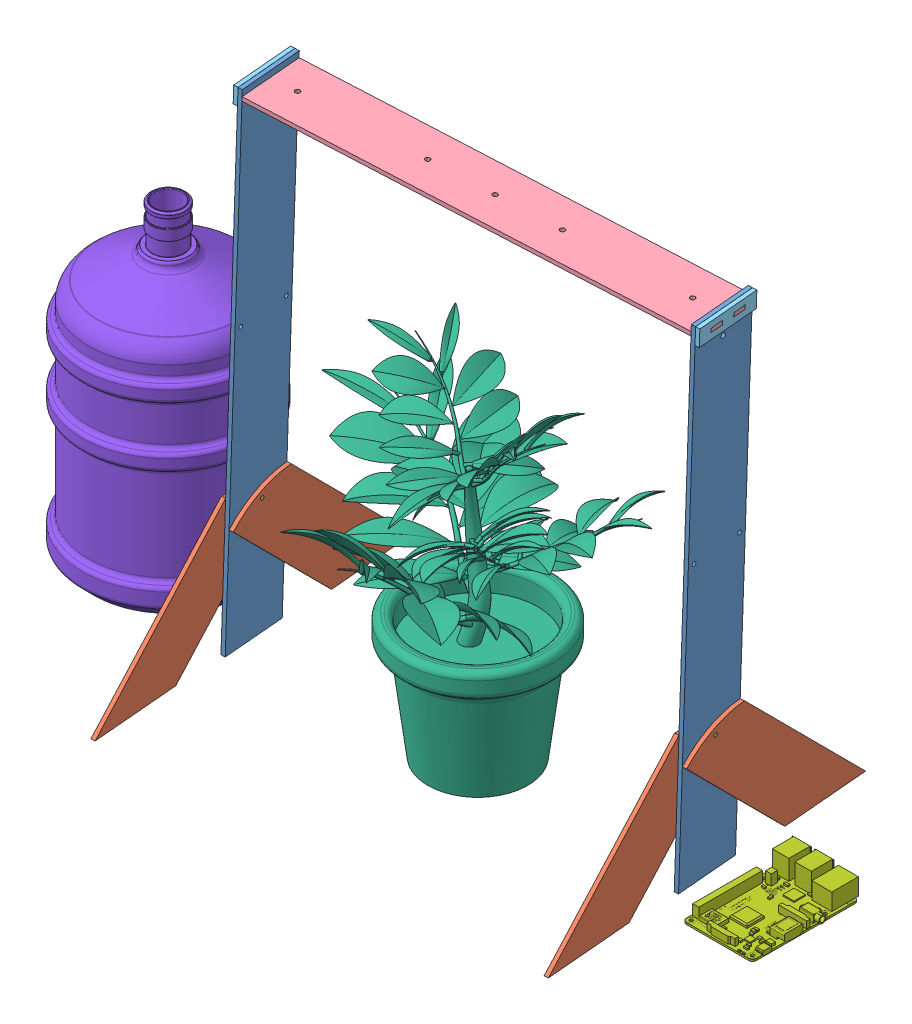
SolidWorks assembly Plant_Frame_Assem, configuration Default. Lengths in mm.
Overall size (564.8 413.02 298.87).
16 component instances, 8 part files, 13 mates.
Components (placement in the parent):
- Assem5^Plant_Frame_Assem-1: Assem5^Plant_Frame_Assem [Default] at (-8.3059 -105.6265 90.45) x (0 -1 0) z (0 0 1) size (400.06 26.56 270.71) (virtual)
  - Left_Right-1: Left_Right [Default] at (-16.0185 -211.6798 -1.7798) x (0.99946 -0.032815 0.001377) z (0.001377 0.083777 0.996484) size (400 3.17 50)
  - Left_Right_Support-1: Left_Right_Support [Default] at (308.6675 -227.6012 -25.9782) x (-0.001377 -0.083777 -0.996484) z (0.99946 -0.032815 0.001377) size (160.36 3.17 110.36)
  - Circular-1: Circular [Default] at (283.6796 -226.8251 -26.0089) x (0.99946 -0.032815 0.001377) z (0.001377 0.083777 0.996484) size (3 9.53 3)
  - Left_Right_Support-2: Left_Right_Support [Default] at (308.9801 -218.1148 -26.7762) x (0.001377 0.083777 0.996484) z (0.99946 -0.032815 0.001377) size (160.36 3.17 110.36)
- Assem5^Plant_Frame_Assem-2: Assem5^Plant_Frame_Assem [Default] at (326.5056 -116.6581 62.2862) x (0 -1 0) z (0 0 1) size (400.06 26.56 270.71) (virtual)
  - Left_Right-1: Left_Right [Default] at (-16.0185 -211.6798 -1.7798) x (0.99946 -0.032815 0.001377) z (0.001377 0.083777 0.996484) size (400 3.17 50)
  - Left_Right_Support-1: Left_Right_Support [Default] at (308.6675 -227.6012 -25.9782) x (-0.001377 -0.083777 -0.996484) z (0.99946 -0.032815 0.001377) size (160.36 3.17 110.36)
  - Circular-1: Circular [Default] at (283.6796 -226.8251 -26.0089) x (0.99946 -0.032815 0.001377) z (0.001377 0.083777 0.996484) size (3 9.53 3)
  - Left_Right_Support-2: Left_Right_Support [Default] at (308.9801 -218.1148 -26.7762) x (0.001377 0.083777 0.996484) z (0.99946 -0.032815 0.001377) size (160.36 3.17 110.36)
- Top-1: Top [Default] at (-53.3616 -103.3121 49.5545) x (-0.995944 0.032815 0.083777) z (-0.083777 0.001377 -0.996484) size (345.7 3.17 50)
- Left_Right_Clamp_3-1: Left_Right_Clamp_3 [Default] at (-223.5773 -102.5843 88.9543) x (-0.083777 0.001377 -0.996484) z (-0.032815 -0.99946 0.001377) size (50 3.17 13.17)
- Left_Right_Clamp_3-2: Left_Right_Clamp_3 [Default] at (117.5527 -113.9991 60.2588) x (-0.083777 0.001377 -0.996484) z (-0.032815 -0.99946 0.001377) size (50 3.17 13.17)
- POT-1: POT [Default] at (-62.6435 -490.8322 -76.7358) size (233.41 266.72 222.71)
- Rpi3Bplus-1: Rpi3Bplus [Default] at (180.3437 -502.3468 76.9406) x (0 0 -1) z (1 0 0) size (87.03 17.52 58.47)
- 20 ltr water bottle-1: 20 ltr water bottle [Default] at (-312.9838 -576.0338 51.5192) size (138 246 138)
Mates (geometry in assembly coordinates):
- Coincident5: coincident anti-aligned: plane of Assem5^Plant_Frame_Assem-1/Left_Right-1 through (-220.3388 -94.6544 48.5518) normal (-0.032815 -0.99946 0.001377); plane of Top-1 through (-53.2574 -100.1388 49.5502) normal (0.032815 0.99946 -0.001377)
- Coincident6: coincident anti-aligned: plane of Assem5^Plant_Frame_Assem-2/Left_Right-1 through (114.4727 -105.686 20.388) normal (-0.032815 -0.99946 0.001377); plane of Top-1 through (-53.2574 -100.1388 49.5502) normal (0.032815 0.99946 -0.001377)
- Coincident7: coincident anti-aligned: plane of Assem5^Plant_Frame_Assem-1/Left_Right-1 through (-219.9857 -89.608 88.6703) normal (-0.995944 0.032815 0.083777); plane of Left_Right_Clamp_3-1 through (-220.4152 -102.6885 88.6883) normal (0.995944 -0.032815 -0.083777)
- Coincident8: coincident anti-aligned: plane of Top-1 through (-53.2574 -100.1388 49.5502) normal (0.032815 0.99946 -0.001377); plane of Left_Right_Clamp_3-1 through (-222.6631 -94.564 58.7826) normal (-0.032815 -0.99946 0.001377)
- Coincident9: coincident anti-aligned: plane of Assem5^Plant_Frame_Assem-1/Left_Right-1 through (-216.8236 -89.7122 88.4043) normal (0.995944 -0.032815 -0.083777); plane of Top-1 through (-219.0821 -94.6751 63.4991) normal (-0.995944 0.032815 0.083777)
- Coincident10: coincident anti-aligned: plane of Assem5^Plant_Frame_Assem-1/Left_Right-1 through (-220.4429 -97.8277 48.5562) normal (0.083777 -0.001377 0.996484); plane of Top-1 through (-54.5141 -100.1181 34.6029) normal (-0.083777 0.001377 -0.996484)
- Coincident11: coincident anti-aligned: plane of Top-1 through (-54.5141 -100.1181 34.6029) normal (-0.083777 0.001377 -0.996484); plane of Left_Right_Clamp_3-1 through (-223.5993 -97.5486 48.8219) normal (0.083777 -0.001377 0.996484)
- Coincident12: coincident anti-aligned: plane of Assem5^Plant_Frame_Assem-2/Left_Right-1 through (117.9879 -100.7438 60.2405) normal (0.995944 -0.032815 -0.083777); plane of Left_Right_Clamp_3-2 through (117.5527 -113.9991 60.2588) normal (-0.995944 0.032815 0.083777)
- Coincident13: coincident: plane of Assem5^Plant_Frame_Assem-2/Left_Right-1 through (114.8258 -100.6396 60.5065) normal (-0.995944 0.032815 0.083777); line of Top-1 through (110.4728 -105.568 10.6892) axis (0.083777 -0.001377 0.996484)
- Coincident14: coincident anti-aligned: plane of Assem5^Plant_Frame_Assem-2/Left_Right-1 through (115.2063 -108.8731 30.3572) normal (0.032815 0.99946 -0.001377); plane of Top-1 through (-53.3616 -103.3121 49.5545) normal (-0.032815 -0.99946 0.001377)
- Coincident15: coincident anti-aligned: plane of Assem5^Plant_Frame_Assem-2/Left_Right-1 through (114.3686 -108.8593 20.3924) normal (0.083777 -0.001377 0.996484); plane of Top-1 through (117.6349 -105.7902 20.122) normal (-0.083777 0.001377 -0.996484)
- Coincident16: coincident anti-aligned: plane of Top-1 through (-53.3616 -103.3121 49.5545) normal (-0.032815 -0.99946 0.001377); plane of Left_Right_Clamp_3-2 through (118.3684 -108.9772 30.0912) normal (0.032815 0.99946 -0.001377)
- Coincident17: coincident anti-aligned: plane of Left_Right_Clamp_3-2 through (117.5307 -108.9635 20.1264) normal (0.083777 -0.001377 0.996484); plane of Top-1 through (117.6349 -105.7902 20.122) normal (-0.083777 0.001377 -0.996484)
